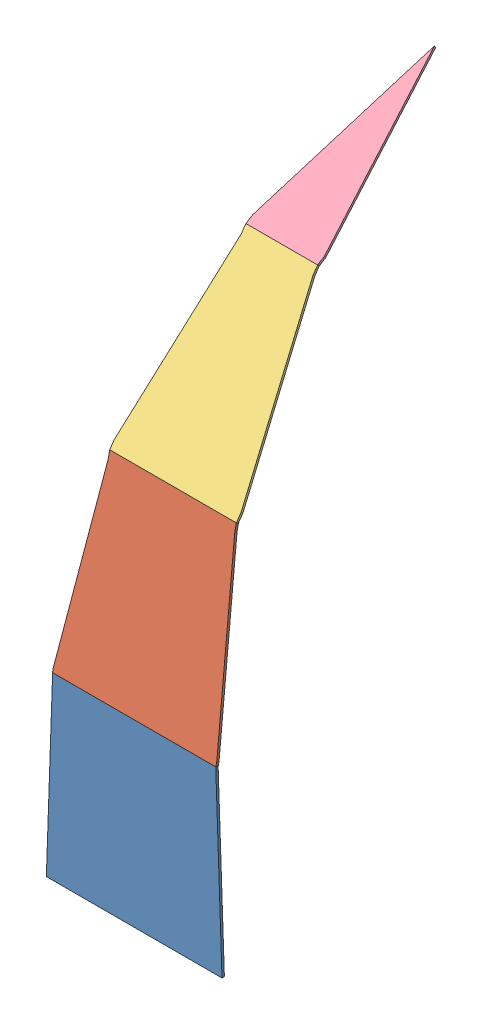
SolidWorks assembly Assem1, configuration Default. Lengths in mm.
Overall size (890 3106.61 1527.47).
4 component instances, 4 part files, 9 mates.
Components (placement in the parent):
- partition1-1: partition1 [Default] at (96.1188 51.7569 226.5524) size (890 910.48 12)
- partition2-2: partition2 [Default] at (127.1788 941.2148 226.5524) x (1 0 0) z (0 0.207912 0.978148) size (827.88 946.84 12)
- partition3-1: partition3 [Default] at (220.2088 1806.9972 42.5247) x (1 0 0) z (0 0.573576 0.819152) size (641.82 960.42 12)
- partition4-1: partition4 [Default] at (359.4388 2527.0667 -461.6734) x (1 0 0) z (0 0.848048 0.529919) size (363.36 911.95 12)
Mates (geometry in assembly coordinates):
- Coincident1: coincident anti-aligned: plane of partition1-1 through (1318.1188 941.2148 226.5524) normal (0 0.994522 -0.104528); plane of partition2-2 through (1439.1788 941.2148 226.5524) normal (0 -0.994522 0.104528)
- Coincident2: coincident aligned: line of partition1-1 through (955.0582 962.2356 426.5524) axis (-1 0 0); line of partition2-2 through (955.0588 962.2356 426.5524) axis (-1 0 0)
- Coincident3: coincident: point of partition1-1; point of partition2-2
- Coincident4: coincident anti-aligned: plane of partition2-2 through (1439.1788 1806.9972 42.5247) normal (0 0.91706 -0.398749); plane of partition3-1 through (1027.2088 1806.9972 42.5247) normal (0 -0.91706 0.398749)
- Coincident5: coincident anti-aligned: line of partition2-2 through (220.2091 1888.3808 229.6942) axis (1 0 0); line of partition3-1 through (862.0288 1888.3808 229.6942) axis (-1 0 0)
- Coincident6: coincident: point of partition2-2; point of partition3-1
- Coincident7: coincident anti-aligned: plane of partition3-1 through (1027.2088 2527.0667 -461.6734) normal (0 0.688355 -0.725374); plane of partition4-1 through (821.4388 2527.0667 -461.6734) normal (0 -0.688355 0.725374)
- Coincident8: coincident aligned: line of partition3-1 through (722.8021 2675.1137 -321.1821) axis (-1 0 0); line of partition4-1 through (722.7988 2675.1137 -321.1821) axis (-1 0 0)
- Coincident9: coincident: point of partition3-1; point of partition4-1
